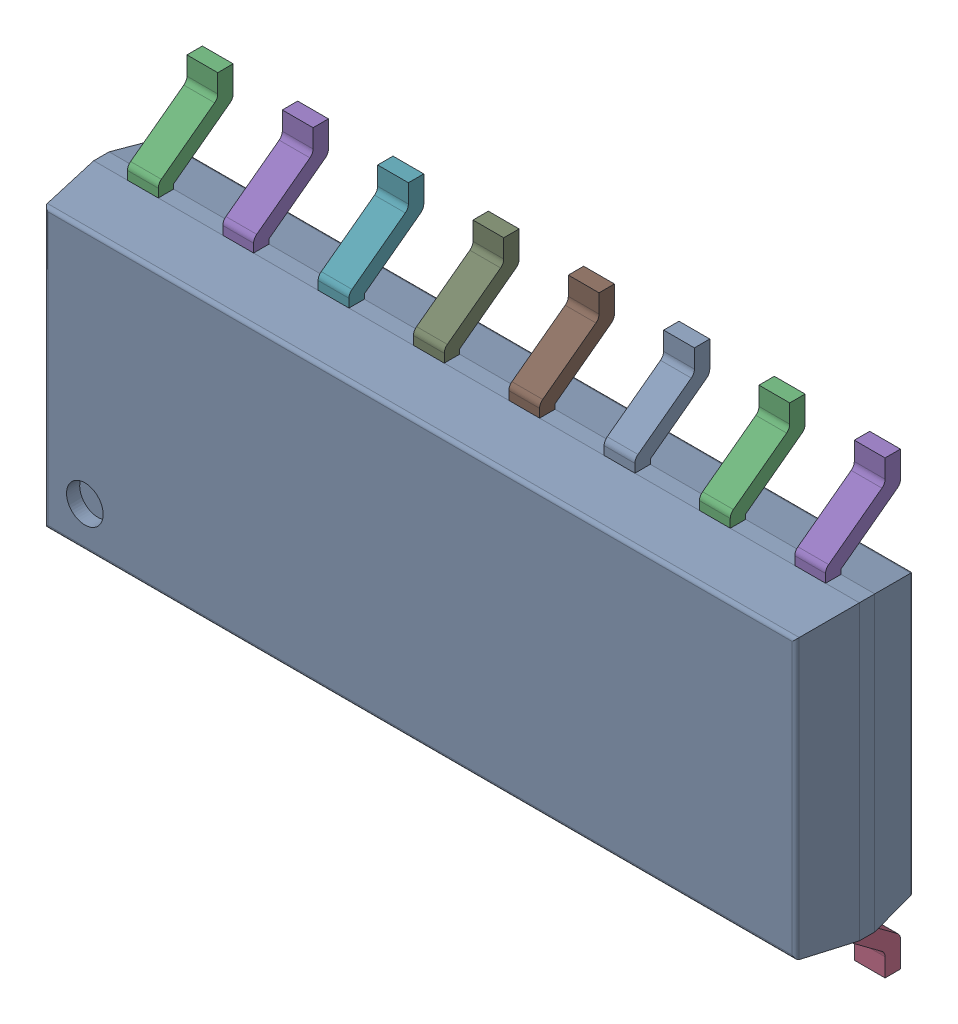
SolidWorks assembly IC16_1.step, configuration Default. Lengths in mm.
Overall size (10.2 6 1.75).
3 component instances, 2 part files, 0 mates.
Components (placement in the parent):
- 6348803008_1.step-11: 6348803008_1.step [Default] at (520.065 271.75 0) x (0 1 0) z (0 0 1) size (6 10.2 1.75)
  - Body-14_1.step-32: Body-14_1.step [Default] at origin size (3.9 10.2 1.57)
  - PinsArrayLR-15_1.step-32: PinsArrayLR-15_1.step [Default] at origin size (6 9.3 1)
